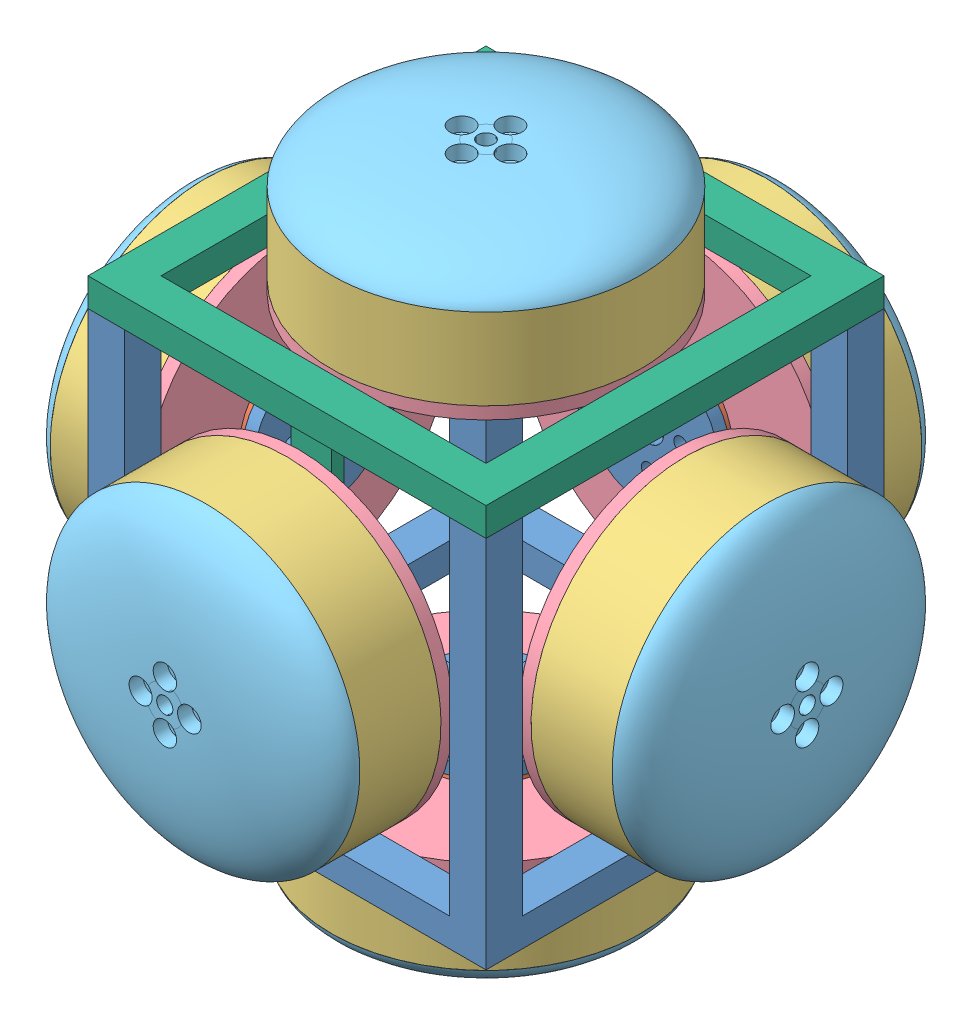
SolidWorks assembly electronics core, configuration Default. Lengths in mm.
Overall size (158.54 160.54 158.54).
32 component instances, 6 part files, 19 mates.
Components (placement in the parent):
- motor frame-1: motor frame [Default] at (28.4837 83.9522 75.0785) size (98 92 98)
- single gyro-1: single gyro [Default] at (16.6911 69.5915 110.0255) size (81.89 81.89 36.27)
  - orange motor-1: orange motor [Default] at (11.7926 14.3607 8.0531) size (27.9 27.9 29.34)
  - alluminum ring-1: alluminum ring [Default] at (11.7926 14.3607 14.2431) x (0.996982 0.077639 0) z (0 0 1) size (76.2 76.2 20)
  - lower gyro motor adapter-1: lower gyro motor adapter [Default] at (11.7926 14.3607 11.2431) x (1 0 0) z (0 -1 0) size (76.2 26.9 76.2)
  - upper gyro motor adapter-1: upper gyro motor adapter [Default] at (11.7926 14.3607 38.1431) x (1 0 0) z (0 -1 0) size (76.55 10.25 76.55)
- single gyro-2: single gyro [Default] at (16.6911 49.0053 60.7179) x (1 0 0) z (0 -1 0) size (81.89 81.89 36.27)
  - orange motor-1: orange motor [Default] at (11.7926 14.3607 8.0531) size (27.9 27.9 29.34)
  - alluminum ring-1: alluminum ring [Default] at (11.7926 14.3607 14.2431) x (0.996982 0.077639 0) z (0 0 1) size (76.2 76.2 20)
  - lower gyro motor adapter-1: lower gyro motor adapter [Default] at (11.7926 14.3607 11.2431) x (1 0 0) z (0 -1 0) size (76.2 26.9 76.2)
  - upper gyro motor adapter-1: upper gyro motor adapter [Default] at (11.7926 14.3607 38.1431) x (1 0 0) z (0 -1 0) size (76.55 10.25 76.55)
- single gyro-3: single gyro [Default] at (63.4307 69.5915 86.8712) x (0 0 -1) z (1 0 0) size (81.89 81.89 36.27)
  - orange motor-1: orange motor [Default] at (11.7926 14.3607 8.0531) size (27.9 27.9 29.34)
  - alluminum ring-1: alluminum ring [Default] at (11.7926 14.3607 14.2431) x (0.996982 0.077639 0) z (0 0 1) size (76.2 76.2 20)
  - lower gyro motor adapter-1: lower gyro motor adapter [Default] at (11.7926 14.3607 11.2431) x (1 0 0) z (0 -1 0) size (76.2 26.9 76.2)
  - upper gyro motor adapter-1: upper gyro motor adapter [Default] at (11.7926 14.3607 38.1431) x (1 0 0) z (0 -1 0) size (76.55 10.25 76.55)
- single gyro-4: single gyro [Default] at (-6.4632 69.5915 63.2859) x (0 0 1) z (-1 0 0) size (81.89 81.89 36.27)
  - orange motor-1: orange motor [Default] at (11.7926 14.3607 8.0531) size (27.9 27.9 29.34)
  - alluminum ring-1: alluminum ring [Default] at (11.7926 14.3607 14.2431) x (0.996982 0.077639 0) z (0 0 1) size (76.2 76.2 20)
  - lower gyro motor adapter-1: lower gyro motor adapter [Default] at (11.7926 14.3607 11.2431) x (1 0 0) z (0 -1 0) size (76.2 26.9 76.2)
  - upper gyro motor adapter-1: upper gyro motor adapter [Default] at (11.7926 14.3607 38.1431) x (1 0 0) z (0 -1 0) size (76.55 10.25 76.55)
- single gyro-5: single gyro [Default] at (40.2764 69.5915 40.1316) x (-1 0 0) z (0 0 -1) size (81.89 81.89 36.27)
  - orange motor-1: orange motor [Default] at (11.7926 14.3607 8.0531) size (27.9 27.9 29.34)
  - alluminum ring-1: alluminum ring [Default] at (11.7926 14.3607 14.2431) x (0.996982 0.077639 0) z (0 0 1) size (76.2 76.2 20)
  - lower gyro motor adapter-1: lower gyro motor adapter [Default] at (11.7926 14.3607 11.2431) x (1 0 0) z (0 -1 0) size (76.2 26.9 76.2)
  - upper gyro motor adapter-1: upper gyro motor adapter [Default] at (11.7926 14.3607 38.1431) x (1 0 0) z (0 -1 0) size (76.55 10.25 76.55)
- single gyro-6: single gyro [Default] at (16.6911 120.8992 89.4392) x (1 0 0) z (0 1 0) size (81.89 81.89 36.27)
  - orange motor-1: orange motor [Default] at (11.7926 14.3607 8.0531) size (27.9 27.9 29.34)
  - alluminum ring-1: alluminum ring [Default] at (11.7926 14.3607 14.2431) x (0.996982 0.077639 0) z (0 0 1) size (76.2 76.2 20)
  - lower gyro motor adapter-1: lower gyro motor adapter [Default] at (11.7926 14.3607 11.2431) x (1 0 0) z (0 -1 0) size (76.2 26.9 76.2)
  - upper gyro motor adapter-1: upper gyro motor adapter [Default] at (11.7926 14.3607 38.1431) x (1 0 0) z (0 -1 0) size (76.55 10.25 76.55)
- motor frame top-1: motor frame top [Default] at (28.4837 88.9522 75.0785) x (-1 0 0) z (0 0 1) size (98 30.26 98)
Mates (geometry in assembly coordinates):
- Coincident3: coincident aligned: plane of motor frame-1 through (28.4837 83.9522 32.0785) normal (0 0 -1); plane of ? through (28.4837 83.9522 32.0785) normal (0 0 -1)
- Distance1: distance = 0.4 mm: plane of motor frame-1 through (78.4837 83.7522 75.0785) normal (0 1 0); plane of ? through (78.4837 84.1522 75.0785) normal (0 -1 0)
- Coincident6: coincident anti-aligned: circle of ?; circle of single gyro-6/orange motor-1
- Concentric1: concentric anti-aligned: circle of ?; circle of single gyro-6/orange motor-1
- Coincident8: coincident aligned: circle of ?; circle of single gyro-3/orange motor-1
- Concentric2: concentric anti-aligned: circle of motor frame-1; circle of single gyro-3/orange motor-1
- Coincident11: coincident aligned: circle of ?; circle of single gyro-5/orange motor-1
- Concentric3: concentric aligned: circle of motor frame-1; circle of single gyro-5/orange motor-1
- Coincident13: coincident aligned: circle of ?; circle of single gyro-1/orange motor-1
- Concentric4: concentric anti-aligned: circle of motor frame-1; circle of single gyro-1/orange motor-1
- Coincident15: coincident aligned: circle of ?; circle of single gyro-4/orange motor-1
- Concentric5: concentric anti-aligned: circle of motor frame-1; circle of single gyro-4/orange motor-1
- Coincident17: coincident anti-aligned: circle of motor frame-1; circle of single gyro-2/orange motor-1
- Concentric6: concentric anti-aligned: circle of motor frame-1; circle of single gyro-2/orange motor-1
- Concentric7: concentric aligned: cylinder of motor frame-1 through (72.9837 120.9522 30.5785) axis (0 1 0) radius 3.125; cylinder of motor frame top-1 through (72.9837 122.9522 30.5785) axis (0 1 0) radius 2.875
- Concentric8: concentric aligned: cylinder of motor frame-1 through (72.9837 120.9522 119.5785) axis (0 1 0) radius 3.125; cylinder of motor frame top-1 through (72.9837 122.9522 119.5785) axis (0 1 0) radius 2.875
- Coincident18: coincident anti-aligned: plane of motor frame-1 through (28.4837 128.9522 25.0785) normal (0 1 0); plane of motor frame top-1 through (28.4837 128.9522 75.0785) normal (0 -1 0)
- Coincident19: coincident anti-aligned: plane of single gyro-6/orange motor-1 through (28.4837 131.9522 75.0785) normal (0 -1 0); circle of motor frame top-1
- Concentric9: concentric aligned: cylinder of single gyro-6/alluminum ring-1 through (28.4837 155.1422 75.0785) axis (0 -1 0) radius 38.1; cylinder of motor frame top-1 through (28.4837 131.9522 75.0785) axis (0 -1 0) radius 17.4733
